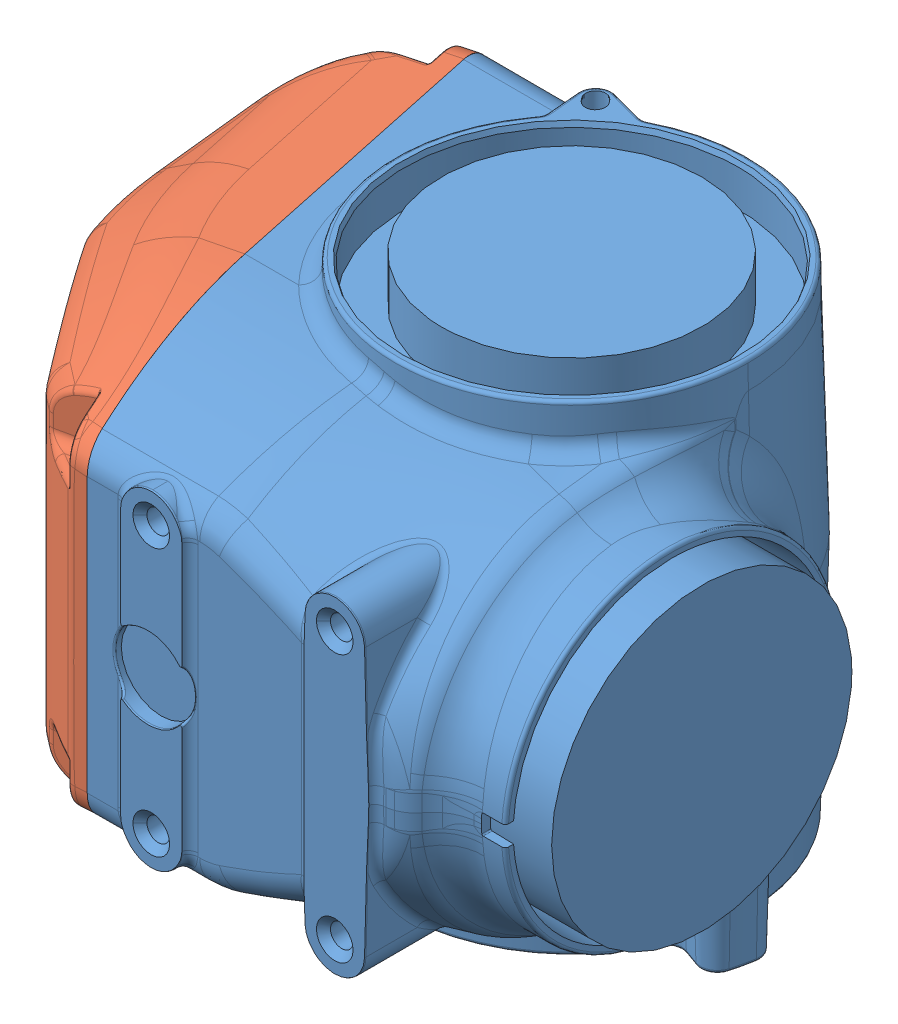
SolidWorks assembly GP7_U_AXIS, configuration Default. Lengths in mm.
Overall size (200.01 147 199.47).
2 component instances, 2 part files, 0 mates.
Components (placement in the parent):
- Uaxis_CASING-1: Uaxis_CASING [Default] at origin size (157.07 147 199.47)
- Uaxis_CASING_COVER-1: Uaxis_CASING_COVER [Default] at (-63.5796 0 13.5142) x (0.207912 0 0.978148) z (0.978148 0 -0.207912) size (158.22 125.51 46.27)
